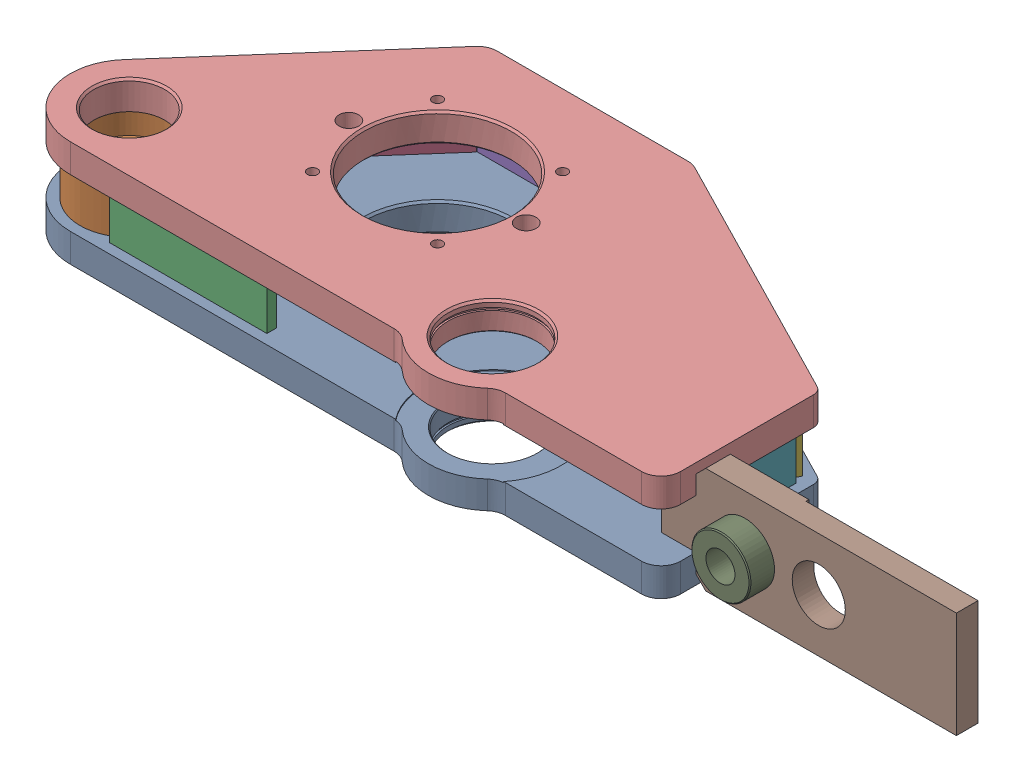
SolidWorks assembly g1_3_1_1_5_2, configuration 默认. Lengths in mm.
Overall size (926 108 318.6).
11 component instances, 11 part files, 0 mates.
Components (placement in the parent):
- g1_3_1_1_5-1_af1_2-1: g1_3_1_1_5-1_af1_2 [默认] at origin size (661 29 318.6)
- g1_3_1_1_5-2_af0_2-1: g1_3_1_1_5-2_af0_2 [默认] at (-213.2 29 0) size (100 50 100)
- g1_3_1_1_5-3_2-1: g1_3_1_1_5-3_2 [默认] at (-103.2 54 50) x (1 0 0) z (0 1 0) size (160 10 50)
- g1_3_1_1_5-4_2-1: g1_3_1_1_5-4_2 [默认] at (-149.9151 54 -132.7301) x (0 1 0) z (-0.659692 0 0.751536) size (50 10 223)
- g1_3_1_1_5-5_2-1: g1_3_1_1_5-5_2 [默认] at (20.5 54 -217) x (1 0 0) z (0 1 0) size (194 10 50)
- g1_3_1_1_5-6_2-1: g1_3_1_1_5-6_2 [默认] at (248.4498 54 -161.5242) x (0 1 0) z (0.890083 0 0.455798) size (50 10 284)
- g1_3_1_1_5-7_2-1: g1_3_1_1_5-7_2 [默认] at (377.8 54 -43.9) x (0 0 -1) z (0 1 0) size (87 10 50)
- g1_3_1_1_5-9_af0_2-1: g1_3_1_1_5-9_af0_2 [默认] at (502.8 54 24.6) x (1 0 0) z (0 1 0) size (300 25 108)
- g1_3_1_1_5-8_2-1: g1_3_1_1_5-8_2 [默认] at (437.8 54 49.6) x (1 0 0) z (0 1 0) size (60 50 60)
- g1_3_1_1_5-1_af0_2-1: g1_3_1_1_5-1_af0_2 [默认] at (0 79 0) size (661 29 318.6)
- g1_3_1_1_5_more_2-1: g1_3_1_1_5_more_2 [默认] at origin size (139.2 108 206.2)
